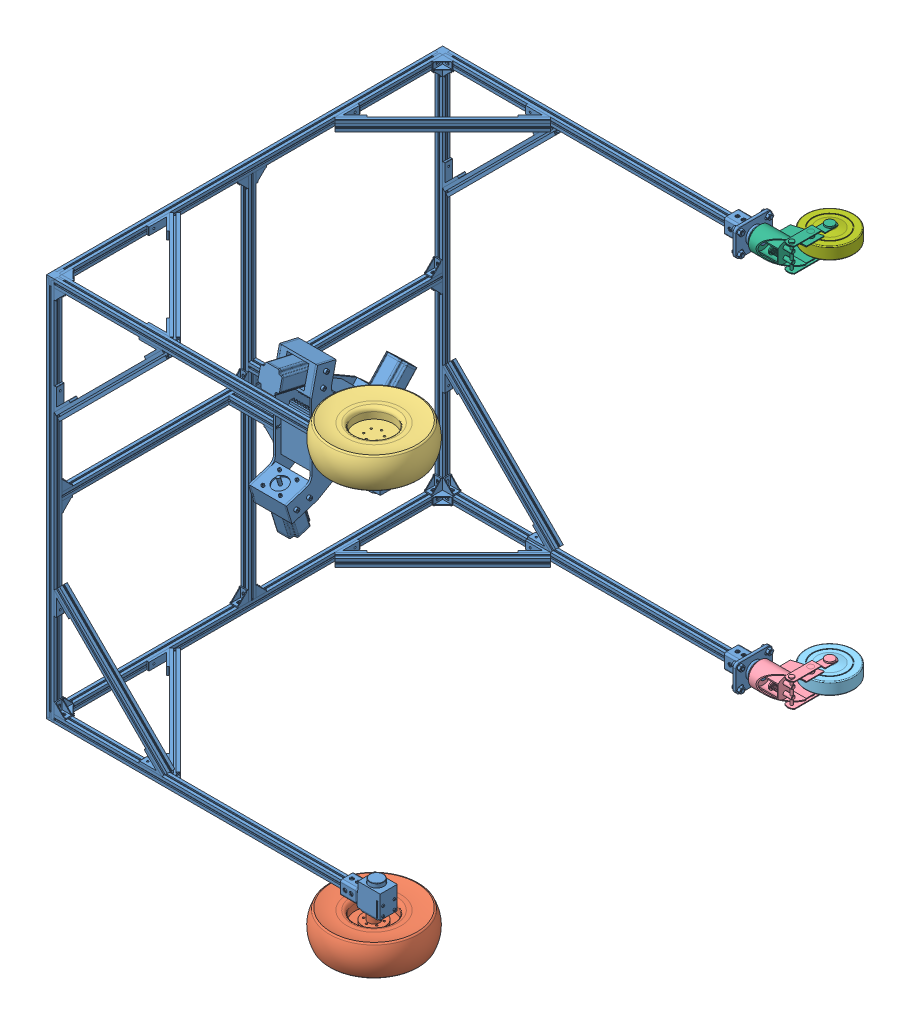
SolidWorks assembly 装配体1, configuration Default. Lengths in mm.
Overall size (1014.86 1201.01 1337.44).
7 component instances, 7 part files, 8 mates.
Components (placement in the parent):
- Base-1: Base [默认] at (153.8383 -97.0811 -329.752) size (890.6 1072.4 1090.2)
- Driving_Wheel_1-1: Driving_Wheel_1 [默认] at (1013.8593 45.6114 1231.8039) x (1 0 0) z (0 1 0) size (257.62 257.62 86.31)
- Driving_Wheel_2-1: Driving_Wheel_2 [默认] at (1013.8593 1154.0114 1231.6593) x (1 0 0) z (0 -1 0) size (257.62 257.62 86.31)
- Link_Idler_Wheel_1-1: Link_Idler_Wheel_1 [默认] at (928.8665 41.2421 177.5322) x (0 -0.057419 0.99835) z (0 0.99835 0.057419) size (146.07 110.26 71.01)
- Idler_Wheel_1-1: Idler_Wheel_1 [默认] at (1090.3592 104.9114 111.5316) x (0 1 0) z (0.688622 0 -0.72512) size (40 125 125)
- Link_Idler_Wheel_2-1: Link_Idler_Wheel_2 [默认] at (928.8665 1031.2421 177.5322) x (0 -0.057419 0.99835) z (0 0.99835 0.057419) size (146.07 110.26 71.01)
- Idler_Wheel_2-1: Idler_Wheel_2 [默认] at (1090.3592 1094.9114 111.5316) x (0 -1 0) z (-0.118719 0 0.992928) size (40 125 125)
Mates (geometry in assembly coordinates):
- 铰链1: hinge anti-aligned: cylinder of Base-1 through (1013.8593 63.6114 1231.8039) axis (0 1 0) radius 3; cylinder of Driving_Wheel_1-1 through (1013.8593 78.6114 1231.8039) axis (0 -1 0) radius 15; plane of Driving_Wheel_1-1 through (1013.8593 78.6114 1231.8039) normal (0 1 0); plane of Base-1 through (1013.8593 78.6114 1231.8039) normal (0 -1 0)
- 铰链3: hinge anti-aligned: cylinder of Base-1 through (1013.8593 1136.0114 1231.6593) axis (0 -1 0) radius 3; cylinder of Driving_Wheel_2-1 through (1013.8593 1121.0114 1231.6593) axis (0 1 0) radius 15; plane of Driving_Wheel_2-1 through (1013.8593 1121.0114 1231.6593) normal (0 -1 0); plane of Base-1 through (1013.8593 1121.0114 1231.6593) normal (0 1 0)
- 铰链4: hinge anti-aligned: cylinder of Link_Idler_Wheel_1-1 through (996.8592 104.9114 211.5316) axis (1 0 0) radius 20; cylinder of Base-1 through (1004.8592 104.9114 211.5316) axis (1 0 0) radius 7.5; plane of Base-1 through (1014.8592 114.5943 207.4705) normal (-1 0 0); plane of Link_Idler_Wheel_1-1 through (1014.8592 104.9114 211.5316) normal (1 0 0)
- 铰链5: hinge anti-aligned: cylinder of Idler_Wheel_1-1 through (1090.3592 84.9114 111.5316) axis (0 1 0) radius 8; cylinder of Link_Idler_Wheel_1-1 through (1090.3592 104.9114 111.5316) axis (0 1 0) radius 8; plane of Link_Idler_Wheel_1-1 through (1077.8592 84.9114 96.5316) normal (0 1 0); plane of Idler_Wheel_1-1 through (1090.3592 84.9114 111.5316) normal (0 -1 0)
- 铰链7: hinge anti-aligned: cylinder of Base-1 through (1004.8592 1094.9114 211.5316) axis (1 0 0) radius 7.5; cylinder of Link_Idler_Wheel_2-1 through (1006.8592 1094.9114 211.5316) axis (1 0 0) radius 30; plane of Base-1 through (1014.8592 1104.5943 207.4705) normal (-1 0 0); plane of Link_Idler_Wheel_2-1 through (1014.8592 1094.9114 211.5316) normal (1 0 0)
- 铰链8: hinge anti-aligned: cylinder of Link_Idler_Wheel_2-1 through (1090.3592 1094.9114 111.5316) axis (0 1 0) radius 8; cylinder of Idler_Wheel_2-1 through (1090.3592 1114.9114 111.5316) axis (0 -1 0) radius 8; plane of Link_Idler_Wheel_2-1 through (1102.8592 1114.9114 96.5316) normal (0 -1 0); plane of Idler_Wheel_2-1 through (1090.3592 1114.9114 111.5316) normal (0 1 0)
- 平行1: parallel aligned: plane of Base-1 through (1020.8592 1053.0114 1231.6316) normal (0 -1 0); plane of Link_Idler_Wheel_2-1 through (1077.8592 1062.9114 221.5316) normal (0 -1 0)
- 平行2: parallel aligned: plane of Base-1 through (1020.8592 146.6114 1231.8316) normal (0 1 0); plane of Link_Idler_Wheel_1-1 through (1102.8592 136.9114 221.5316) normal (0 1 0)
